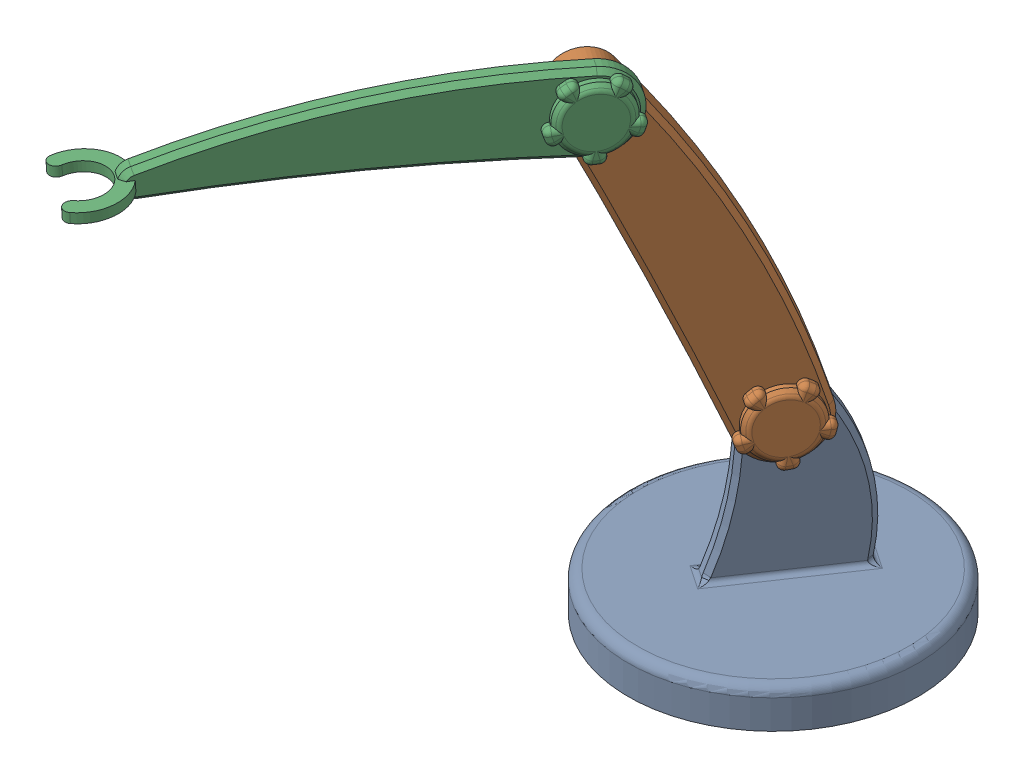
SolidWorks assembly TWO_link_ROBOTIC_ARM_ASSEMBLY, configuration Default. Lengths in mm.
Overall size (253.5 278.42 356.27).
3 component instances, 3 part files, 5 mates.
Components (placement in the parent):
- Part_0_LINK_0-1: Part_0_LINK_0 [Default] x (-0.560298 0 0.828291) z (-0.828291 0 -0.560298) size (150 115 150)
- Part_1_Arm_1-1: Part_1_Arm_1 [Default] at (-9.9997 176.8467 37.0922) x (-0.239451 0.904079 0.353983) z (0.828291 0 0.560298) size (205 46.17 30.27)
- Part_2_Arm_2-1: Part_2_Arm_2 [Default] at (-67.561 249.2973 144.495) x (-0.559548 -0.05172 0.827183) z (0.828291 0 0.560298) size (220.36 43.32 40)
Mates (geometry in assembly coordinates):
- Coincident1: coincident anti-aligned: plane of Part_2_Arm_2-1 through (-102.6049 -329.2045 187.3768) normal (-0.828291 0 -0.560298); plane of Part_1_Arm_1-1 through (-755.4775 -363.3143 1152.5223) normal (0.828291 0 0.560298)
- Concentric1: concentric aligned: cylinder of Part_1_Arm_1-1 through (-24.1409 253.6935 71.383) axis (-0.828291 0 -0.560298) radius 15; cylinder of Part_2_Arm_2-1 through (-15.858 253.6935 76.986) axis (-0.828291 0 -0.560298) radius 20
- Coincident3: coincident anti-aligned: plane of Part_1_Arm_1-1 through (-767.9019 -363.3143 1144.1178) normal (-0.828291 0 -0.560298); plane of Part_0_LINK_0-1 through (-30.305 41.3028 53.7239) normal (0.828291 0 0.560298)
- Concentric2: concentric anti-aligned: cylinder of Part_1_Arm_1-1 through (16.5658 100 11.206) axis (-0.828291 0 -0.560298) radius 20; cylinder of Part_0_LINK_0-1 through (-4.1415 100 -2.8015) axis (0.828291 0 0.560298) radius 15
- Coincident7: coincident aligned: plane of Part_0_LINK_0-1 through (0 0 0) normal (0 1 0)
